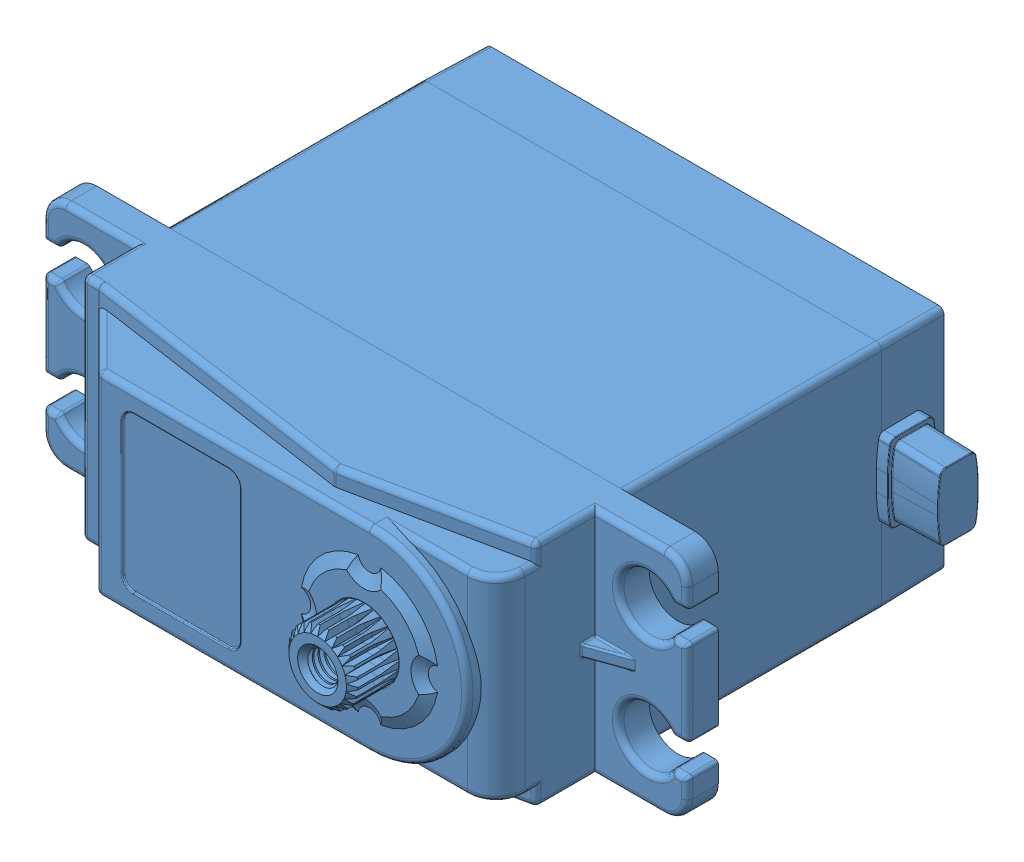
SolidWorks assembly Servo_SPT5435LV, configuration Default. Lengths in mm.
Overall size (56.03 20 44.5).
3 component instances, 2 part files, 0 mates.
Components (placement in the parent):
- Servo_SPT5435LV.step-1: Servo_SPT5435LV.step [Default] at origin size (56.03 20 44.5)
  - Component1.step-1: Component1.step [Default] at (-20 10 0) x (1 0 0) z (0 1 0) size (56.03 44.5 20)
  - pan_head_phillip_mc_screw_m2 v3 (1).step-1: pan_head_phillip_mc_screw_m2 v3 (1).step [Default] at (-17.8711 8.1803 1.3) x (1 0 0) z (0 1 0) size (38.8 8.3 18.8)
